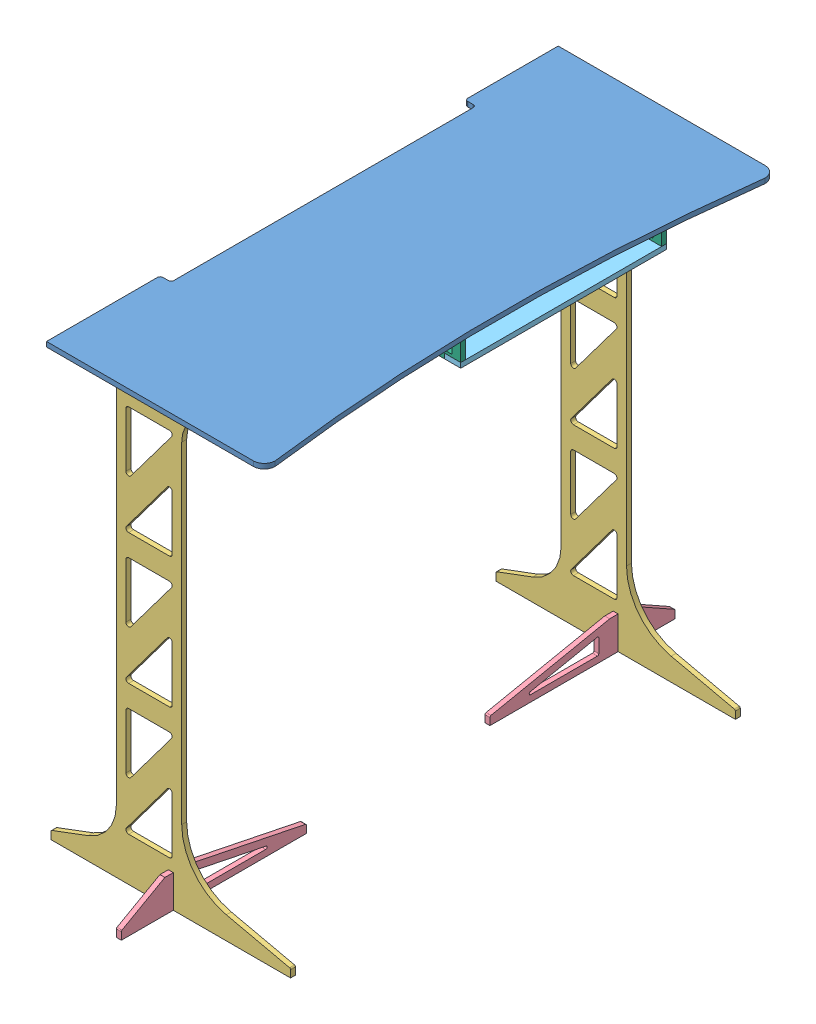
SolidWorks assembly StandupDesk, configuration Default. Lengths in mm.
Overall size (571.5 1071.88 1295.4).
11 component instances, 7 part files, 30 mates.
Components (placement in the parent):
- Base-2: Base [Default] at (1303.5438 611.8616 1017.8967) x (1 0 0) z (0 0 -1) size (508 11.43 1193.8)
- LegSupport-1: LegSupport [Default] at (205.5653 600.4316 1475.0967) x (0 0 1) z (0 1 0) size (254 11.56 57.15)
- LegSupport-2: LegSupport [Default] at (217.1223 600.4316 560.6967) x (0 0 -1) z (0 1 0) size (254 11.56 57.15)
- Leg-1: Leg [Default] at (211.3438 606.7816 491.4182) size (558.8 1066.8 11.56)
- Leg-2: Leg [Default] at (215.0244 606.7816 1532.8182) size (558.8 1066.8 11.56)
- GroundSupport-1: GroundSupport [Default] at (298.1459 -460.0184 1538.5967) x (0 0 -1) z (1 0 0) size (431.8 76.2 11.56)
- GroundSupport-2: GroundSupport [Default] at (306.0223 -460.0184 497.1967) x (0 0 1) z (-1 0 0) size (431.8 76.2 11.56)
- ComputerBase-2: ComputerBase [Default] at (351.0438 493.6246 827.3967) x (0 0 1) z (-1 0 0) size (480.31 11.56 316.36)
- ComputerSide-1: ComputerSide [Default] at (370.0938 555.9816 598.7967) x (-1 0 0) z (0 -1 0) size (316.48 11.56 113.16)
- ComputerSide-2: ComputerSide [Default] at (370.0938 555.9816 1067.5537) x (-1 0 0) z (0 -1 0) size (316.48 11.56 113.16)
- ComputerBack-1: ComputerBack [Default] at (187.0868 493.6246 827.3967) x (0 0 -1) z (0 -1 0) size (457.2 11.56 62.36)
Mates (geometry in assembly coordinates):
- Coincident1: coincident anti-aligned: plane of Base-2 through (1303.5438 606.7816 1017.8967) normal (0 -1 0); plane of LegSupport-1 through (217.1223 606.7816 1386.1967) normal (0 1 0)
- Coincident2: coincident anti-aligned: plane of Base-2 through (217.1223 606.7816 1532.8182) normal (-1 0 0); plane of LegSupport-1 through (217.1223 600.4316 1475.0967) normal (1 0 0)
- Coincident3: coincident anti-aligned: plane of Base-2 through (217.1223 606.7816 1386.1967) normal (0 0 1); plane of LegSupport-1 through (217.1223 600.4316 1386.1967) normal (0 0 -1)
- Coincident4: coincident anti-aligned: plane of Base-2 through (1303.5438 606.7816 1017.8967) normal (0 -1 0); plane of LegSupport-2 through (205.5653 606.7816 649.5967) normal (0 1 0)
- Coincident5: coincident: line of Base-2 through (217.1223 600.4316 649.5967) axis (0 0 -1); plane of LegSupport-2 through (217.1223 600.4316 560.6967) normal (1 0 0)
- Coincident6: coincident anti-aligned: plane of Base-2 through (217.1223 606.7816 649.5967) normal (0 0 -1); plane of LegSupport-2 through (205.5653 600.4316 649.5967) normal (0 0 1)
- Coincident7: coincident anti-aligned: plane of Base-2 through (1303.5438 606.7816 1017.8967) normal (0 -1 0); plane of Leg-1 through (205.5653 606.7816 502.9752) normal (0 1 0)
- Coincident8: coincident anti-aligned: plane of Base-2 through (135.1438 606.7816 491.4182) normal (0 0 1); plane of Leg-1 through (211.3438 606.7816 491.4182) normal (0 0 -1)
- Coincident9: coincident anti-aligned: plane of Base-2 through (135.1438 606.7816 502.9752) normal (1 0 0); plane of Leg-1 through (135.1438 606.7816 502.9752) normal (-1 0 0)
- Coincident10: coincident anti-aligned: plane of Base-2 through (1303.5438 606.7816 1017.8967) normal (0 -1 0); plane of Leg-2 through (220.8029 606.7816 1544.3752) normal (0 1 0)
- Coincident11: coincident anti-aligned: plane of Base-2 through (217.1223 606.7816 1532.8182) normal (0 0 1); plane of Leg-2 through (215.0244 606.7816 1532.8182) normal (0 0 -1)
- Coincident12: coincident anti-aligned: plane of Base-2 through (516.1438 606.7816 1532.8182) normal (-1 0 0); plane of Leg-2 through (516.1438 606.7816 1544.3752) normal (1 0 0)
- Coincident13: coincident anti-aligned: plane of Leg-2 through (309.7029 -460.0184 1532.8182) normal (-1 0 0); plane of GroundSupport-1 through (309.7029 -460.0184 1538.5967) normal (1 0 0)
- Coincident14: coincident anti-aligned: plane of Leg-2 through (309.7029 -396.5184 1532.8182) normal (0 -1 0); plane of GroundSupport-1 through (309.7029 -396.5184 1544.3752) normal (0 1 0)
- Coincident15: coincident anti-aligned: plane of Leg-2 through (215.0244 606.7816 1544.3752) normal (0 0 1); plane of GroundSupport-1 through (309.7029 -383.8184 1544.3752) normal (0 0 -1)
- Coincident16: coincident anti-aligned: plane of Leg-1 through (306.0223 -396.5184 491.4182) normal (0 -1 0); plane of GroundSupport-2 through (294.4653 -396.5184 491.4182) normal (0 1 0)
- Coincident17: coincident anti-aligned: plane of Leg-1 through (306.0223 -460.0184 491.4182) normal (-1 0 0); plane of GroundSupport-2 through (306.0223 -460.0184 497.1967) normal (1 0 0)
- Coincident18: coincident anti-aligned: plane of Leg-1 through (211.3438 606.7816 502.9752) normal (0 0 1); plane of GroundSupport-2 through (294.4653 -396.5184 502.9752) normal (0 0 -1)
- Coincident19: coincident anti-aligned: plane of ComputerBase-2 through (236.7438 505.1816 598.7967) normal (0 0 -1); plane of ComputerSide-1 through (370.0938 555.9816 598.7967) normal (0 0 1)
- Coincident20: coincident anti-aligned: plane of ComputerBase-2 through (465.3438 505.1816 598.7967) normal (-1 0 0); plane of ComputerSide-1 through (465.3438 505.1816 587.2397) normal (1 0 0)
- Coincident21: coincident anti-aligned: plane of ComputerBase-2 through (351.0438 505.1816 827.3967) normal (0 1 0); plane of ComputerSide-1 through (503.4438 505.1816 587.2397) normal (0 -1 0)
- Coincident22: coincident anti-aligned: plane of ComputerBase-2 through (351.0438 505.1816 827.3967) normal (0 1 0); plane of ComputerSide-2 through (503.4438 505.1816 1055.9967) normal (0 -1 0)
- Coincident23: coincident anti-aligned: plane of ComputerBase-2 through (465.3438 505.1816 1055.9967) normal (-1 0 0); plane of ComputerSide-2 through (465.3438 505.1816 1055.9967) normal (1 0 0)
- Coincident24: coincident anti-aligned: plane of ComputerBase-2 through (236.7438 505.1816 1055.9967) normal (0 0 1); plane of ComputerSide-2 through (370.0938 555.9816 1055.9967) normal (0 0 -1)
- Coincident25: coincident anti-aligned: plane of Base-2 through (1303.5438 606.7816 1017.8967) normal (0 -1 0); plane of ComputerSide-1 through (503.4438 606.7816 587.2397) normal (0 1 0)
- Coincident26: coincident anti-aligned: plane of Base-2 through (503.4438 606.7816 587.2397) normal (0 0 1); plane of ComputerSide-1 through (370.0938 555.9816 587.2397) normal (0 0 -1)
- Coincident27: coincident anti-aligned: plane of Base-2 through (236.7438 606.7816 587.2397) normal (1 0 0); plane of ComputerSide-1 through (236.7438 493.6246 587.2397) normal (-1 0 0)
- Coincident28: coincident anti-aligned: plane of ComputerBase-2 through (198.6438 505.1816 649.5967) normal (-1 0 0); plane of ComputerBack-1 through (198.6438 493.6246 827.3967) normal (1 0 0)
- Coincident29: coincident anti-aligned: plane of ComputerBase-2 through (198.6438 505.1816 1005.1967) normal (0 0 -1); plane of ComputerBack-1 through (198.6438 493.6246 1005.1967) normal (0 0 1)
- Coincident30: coincident anti-aligned: plane of ComputerBase-2 through (351.0438 505.1816 827.3967) normal (0 1 0); plane of ComputerBack-1 through (198.6438 505.1816 1005.1967) normal (0 -1 0)
